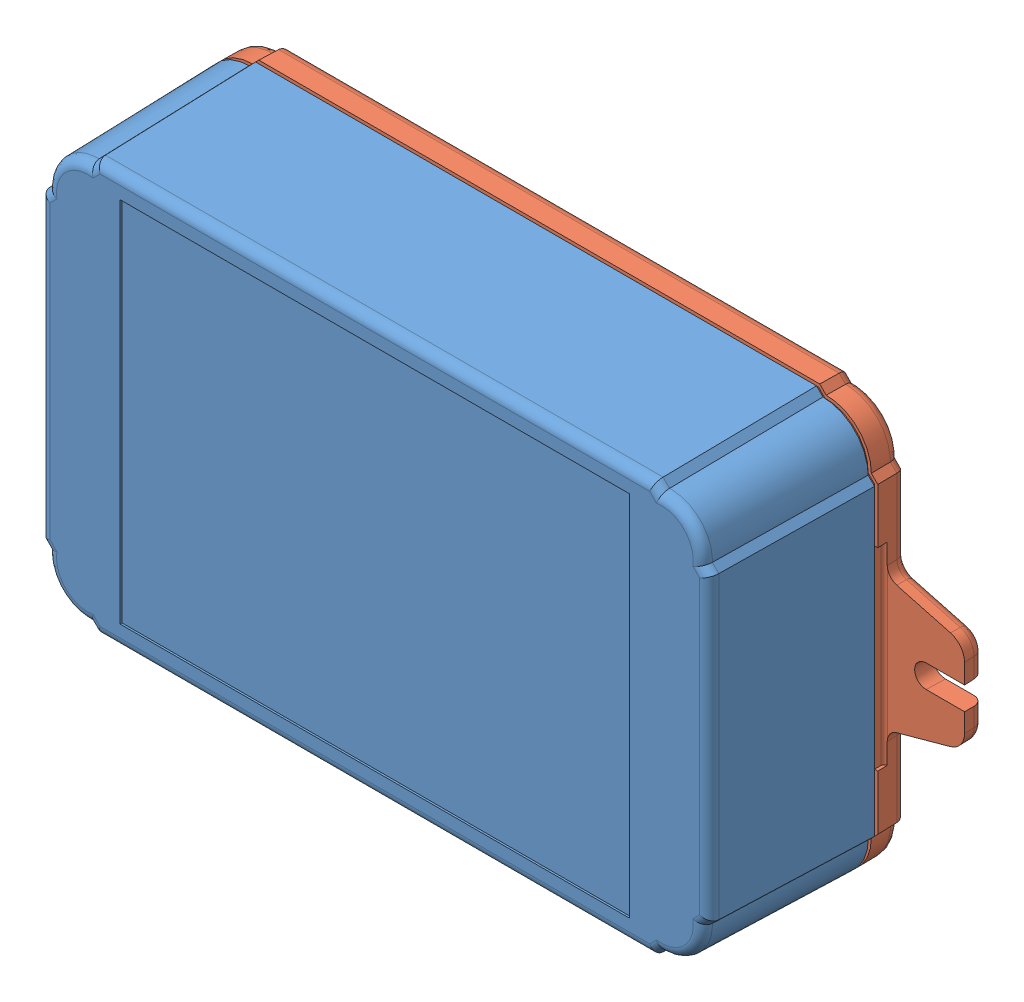
SolidWorks assembly Battery_box_RL6165-F, configuration Default. Lengths in mm.
Overall size (128.92 65 30).
7 component instances, 3 part files, 0 mates.
Components (placement in the parent):
- Battery_box_RL6165-F.stp-1: Battery_box_RL6165-F.stp [Default] at origin size (128.92 65 30)
  - RL6165-B v0 130902.stp-1: RL6165-B v0 130902.stp [Default] at origin size (105 65 25)
  - RL6175-TF v0 130902.stp-1: RL6175-TF v0 130902.stp [Default] at (0 0 -0.5) x (-1 0 0) z (0 0 -1) size (128.92 65 7.8)
  - (screw M2.6X 20mm FH).stp-1: (screw M2.6X 20mm FH).stp [Default] at (-44.5 -24.5 -3) x (0 -1 0) z (1 0 0) size (5.09 17.77 5.09)
  - (screw M2.6X 20mm FH).stp-2: (screw M2.6X 20mm FH).stp [Default] at (-44.5 24.5 -3) x (0 -1 0) z (1 0 0) size (5.09 17.77 5.09)
  - (screw M2.6X 20mm FH).stp-3: (screw M2.6X 20mm FH).stp [Default] at (44.5 -24.5 -3) x (0 -1 0) z (1 0 0) size (5.09 17.77 5.09)
  - (screw M2.6X 20mm FH).stp-4: (screw M2.6X 20mm FH).stp [Default] at (44.5 24.5 -3) x (0 -1 0) z (1 0 0) size (5.09 17.77 5.09)
